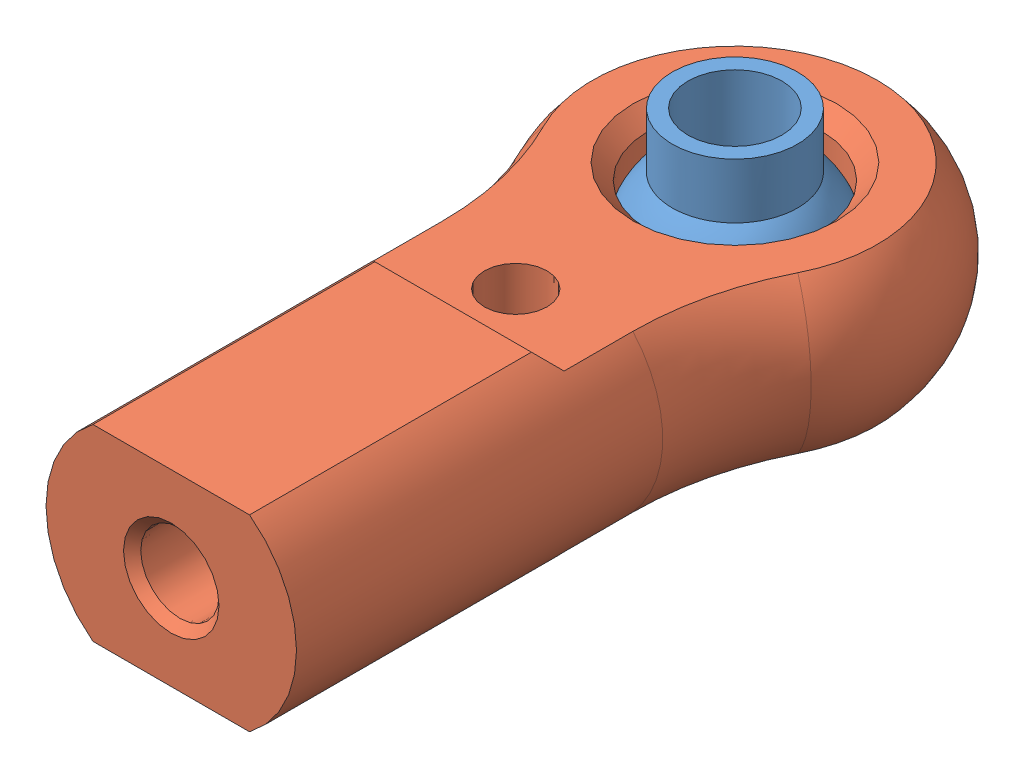
SolidWorks assembly Assem2, configuration Default. Lengths in mm.
Overall size (11 8 23.5).
2 component instances, 2 part files, 4 mates.
Components (placement in the parent):
- balljoint-ball-1: balljoint-ball [Default] at origin size (6 8 6)
- balljoint-housing-1: balljoint-housing [Default] at origin size (11 6 23.5)
Mates (geometry in assembly coordinates):
- Coincident1: coincident aligned: plane of balljoint-housing-1 through (0 0 0) normal (0 1 0); plane of assembly through (0 0 0) normal (0 1 0)
- Coincident2: coincident aligned: plane of balljoint-housing-1 through (0 0 0) normal (1 0 0); plane of assembly through (0 0 0) normal (1 0 0)
- Coincident3: coincident aligned: plane of balljoint-housing-1 through (0 0 0) normal (0 0 1); plane of assembly through (0 0 0) normal (0 0 1)
- Concentric1: concentric: sphere of balljoint-ball-1; sphere of balljoint-housing-1
